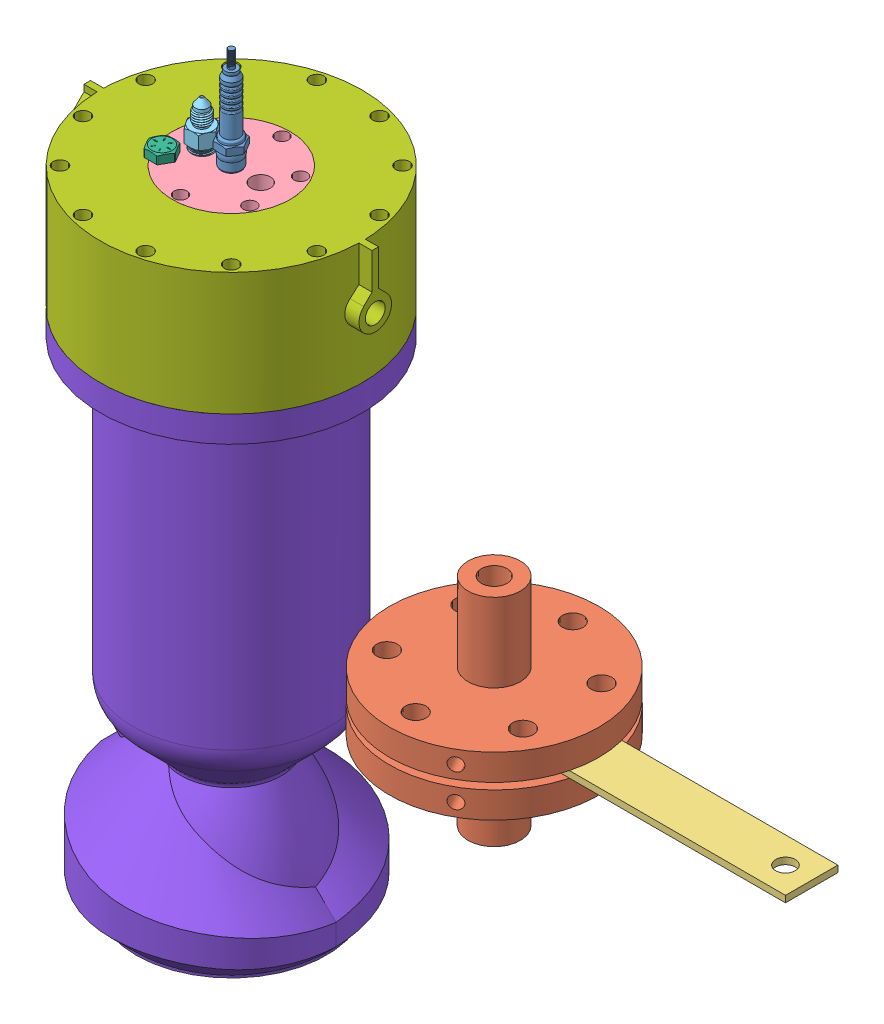
SolidWorks assembly regen additive coax swirl engine 4, configuration Default. Lengths in mm.
Overall size (351.39 380.41 138.79).
10 component instances, 8 part files, 13 mates.
Components (placement in the parent):
- SparkPlug-1: SparkPlug [Default] at (0 53.8263 0) x (0.883262 0 -0.46888) z (0.46888 0 0.883262) size (15.5 63.67 13.54)
- orifice_flow_meter-1: orifice_flow_meter [Default] at (127.5493 -41.9924 0) x (0 0 -1) z (1 0 0) size (138.79 104.77 223.38)
  - orifice_flow_meter_flange-1: orifice_flow_meter_flange [Default] at origin size (101.6 50.8 101.6)
  - 2206N11_Flange-Mount Flow-Control Orifice-1: 2206N11_Flange-Mount Flow-Control Orifice [2206N11] at (0 -52.3875 0) x (1 0 0) z (0 -1 0) size (53.98 180.97 3.17)
  - orifice_flow_meter_flange-2: orifice_flow_meter_flange [Default] at (0 -104.775 0) x (0.5 0 -0.866025) z (-0.866025 0 -0.5) size (101.6 50.8 101.6)
- addative igniter 2-1: addative igniter 2 [Default] at origin size (57.15 66.67 57.15)
- 50715K411_0.125AN-0.125NPT-1: 50715K411_0.125AN-0.125NPT [50715K411] at (-14.2875 74.295 0) x (0 1 0) z (-0.82654 0 0.562878) size (28.28 12.83 11.11)
- 92620A566_0.25-28_hex_bolt-1: 92620A566_0.25-28_hex_bolt [92620A566] at (-21.3096 66.675 12.3031) x (0 -1 0) z (0 0 1) size (43 12.66 11.11)
- addative coax swirl injector10-1: addative coax swirl injector10 [Default] at origin size (139.7 68.76 127)
- slot cooling jacket 14-1: slot cooling jacket 14 [Default] at (0 7.1318 0) size (127 271.42 127)
Mates (geometry in assembly coordinates):
- Coincident9: coincident anti-aligned: plane of orifice_flow_meter-1 through (127.5493 -41.9924 0) normal (0 0 -1)
- Concentric11: concentric anti-aligned: cylinder of SparkPlug-1 through (0 53.8263 0) axis (0 -1 0) radius 5; cylinder of addative igniter 2-1 through (0 66.675 0) axis (0 1 0) radius 3.3
- Coincident14: coincident anti-aligned: plane of SparkPlug-1 through (-2.2227 66.675 -4.1871) normal (0 -1 0); plane of addative igniter 2-1 through (0 66.675 0) normal (0 1 0)
- Concentric14: concentric anti-aligned: cylinder of addative igniter 2-1 through (-14.2875 66.675 0) axis (0 1 0) radius 4.2164; cylinder of 50715K411_0.125AN-0.125NPT-1 through (-14.2875 69.85 0) axis (0 -1 0) radius 2.413
- Distance6: distance = 3.175 mm anti-aligned: plane of addative igniter 2-1 through (0 66.675 0) normal (0 1 0); plane of 50715K411_0.125AN-0.125NPT-1 through (-24.2969 69.85 -4.8269) normal (0 -1 0)
- Concentric15: concentric aligned: cylinder of addative igniter 2-1 through (-21.3096 66.675 12.3031) axis (0 1 0) radius 3.175; cylinder of 92620A566_0.25-28_hex_bolt-1 through (-21.3096 28.575 12.3031) axis (0 1 0) radius 3.175
- Coincident18: coincident anti-aligned: plane of addative igniter 2-1 through (0 66.675 0) normal (0 1 0); plane of 92620A566_0.25-28_hex_bolt-1 through (-14.8938 66.675 12.3031) normal (0 -1 0)
- Coincident19: coordinate: point of addative coax swirl injector10-1
- Concentric16: concentric anti-aligned: cylinder of addative igniter 2-1 through (0 66.675 0) axis (0 1 0) radius 6.35; cylinder of addative coax swirl injector10-1 through (0 0 0) axis (0 -1 0) radius 7.1437
- Coincident20: coincident aligned: cone of addative igniter 2-1 through (0 47.625 0) axis (0 -1 0); cone of addative coax swirl injector10-1 through (0 26.1937 0) axis (0 -1 0)
- Concentric17: concentric aligned: cylinder of addative igniter 2-1 through (0 66.675 24.6062) axis (0 1 0) radius 3.175; cylinder of addative coax swirl injector10-1 through (0 42.0568 24.6062) axis (0 1 0) radius 1.7272
- Concentric19: concentric aligned: cylinder of addative coax swirl injector10-1 through (0 0 0) axis (0 -1 0) radius 63.5; cylinder of slot cooling jacket 14-1 through (0 7.1318 0) axis (0 -1 0) radius 63.5
- Coincident22: coincident anti-aligned: plane of addative coax swirl injector10-1 through (-49.2125 7.1318 0) normal (0 -1 0); plane of slot cooling jacket 14-1 through (-42.8625 7.1318 0) normal (0 1 0)
